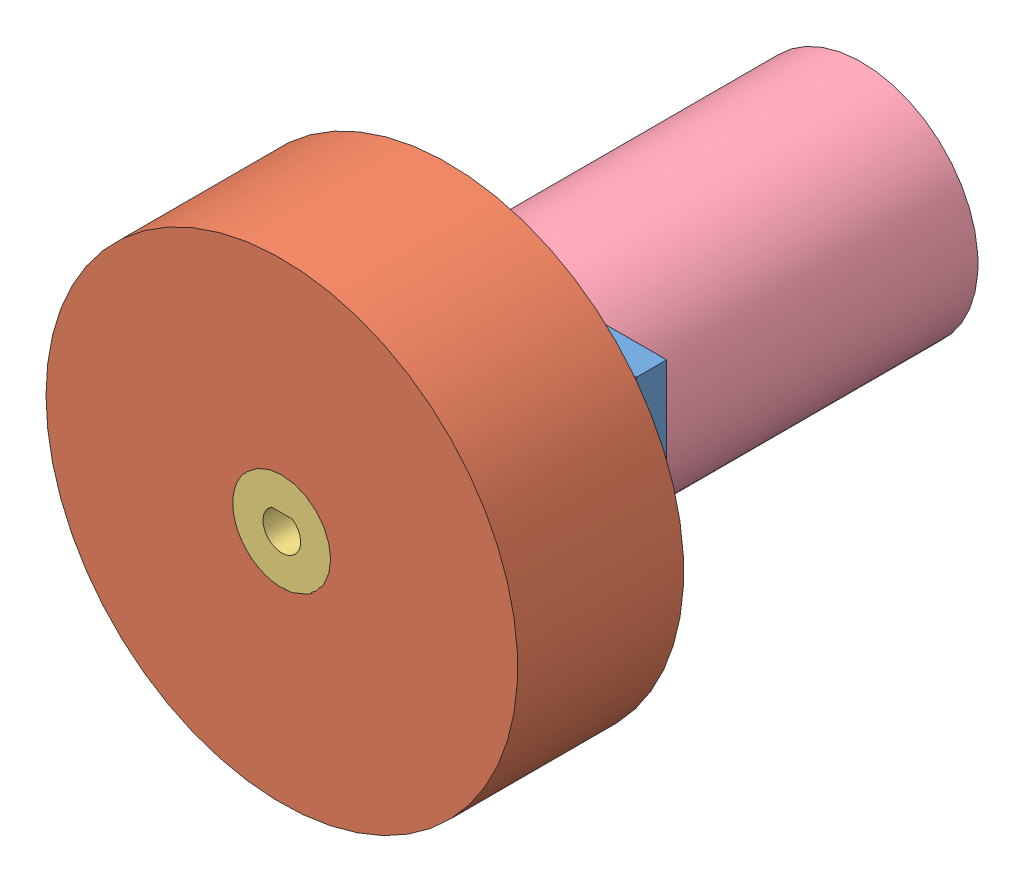
SolidWorks assembly full_pillow, configuration Default. Lengths in mm.
Overall size (75 75 92.2).
4 component instances, 4 part files, 7 mates.
Components (placement in the parent):
- mancal-1: mancal [Default] at (-12.6936 10.2964 49.8287) size (38 38 4.8)
- roda-1: roda [Default] at (-19.6936 29.2964 56.2287) size (75 75 26.4)
- bucha-1: bucha [Default] at (-19.6936 29.2964 82.6287) x (-1 0 0) z (0 -1 0) size (15.6 26 15.6)
- motor-1: motor [Default] at (-19.6936 29.2964 -9.5713) size (37 37 71)
Mates (geometry in assembly coordinates):
- Coincident4: coincident anti-aligned: plane of mancal-1 through (-31.6936 48.2964 47.4287) normal (0 0 -1); plane of motor-1 through (-19.6936 29.2964 47.4287) normal (0 0 1)
- Concentric3: concentric anti-aligned: cylinder of mancal-1 through (-19.6936 29.2964 47.4287) axis (0 0 1) radius 6; cylinder of motor-1 through (-19.6936 29.2964 61.4287) axis (0 0 -1) radius 3
- Concentric4: concentric anti-aligned: cylinder of bucha-1 through (-19.6936 29.2964 56.6287) axis (0 0 1) radius 3; cylinder of motor-1 through (-19.6936 29.2964 61.4287) axis (0 0 -1) radius 3
- Coincident5: coincident anti-aligned: plane of bucha-1 through (-19.6936 31.7964 56.6287) normal (0 -1 0); plane of motor-1 through (-19.6936 31.7964 61.4287) normal (0 1 0)
- Concentric5: concentric anti-aligned: cylinder of roda-1 through (-19.6936 29.2964 82.6287) axis (0 0 -1) radius 7.75; cylinder of bucha-1 through (-19.6936 29.2964 56.6287) axis (0 0 1) radius 7.8
- Coincident7: coincident aligned: plane of roda-1 through (-19.6936 29.2964 82.6287) normal (0 0 1); plane of bucha-1 through (-19.6936 29.2964 82.6287) normal (0 0 1)
- Distance1: distance = 4 mm anti-aligned: plane of roda-1 through (-19.6936 29.2964 56.2287) normal (0 0 -1); plane of mancal-1 through (-31.6936 48.2964 52.2287) normal (0 0 1)
